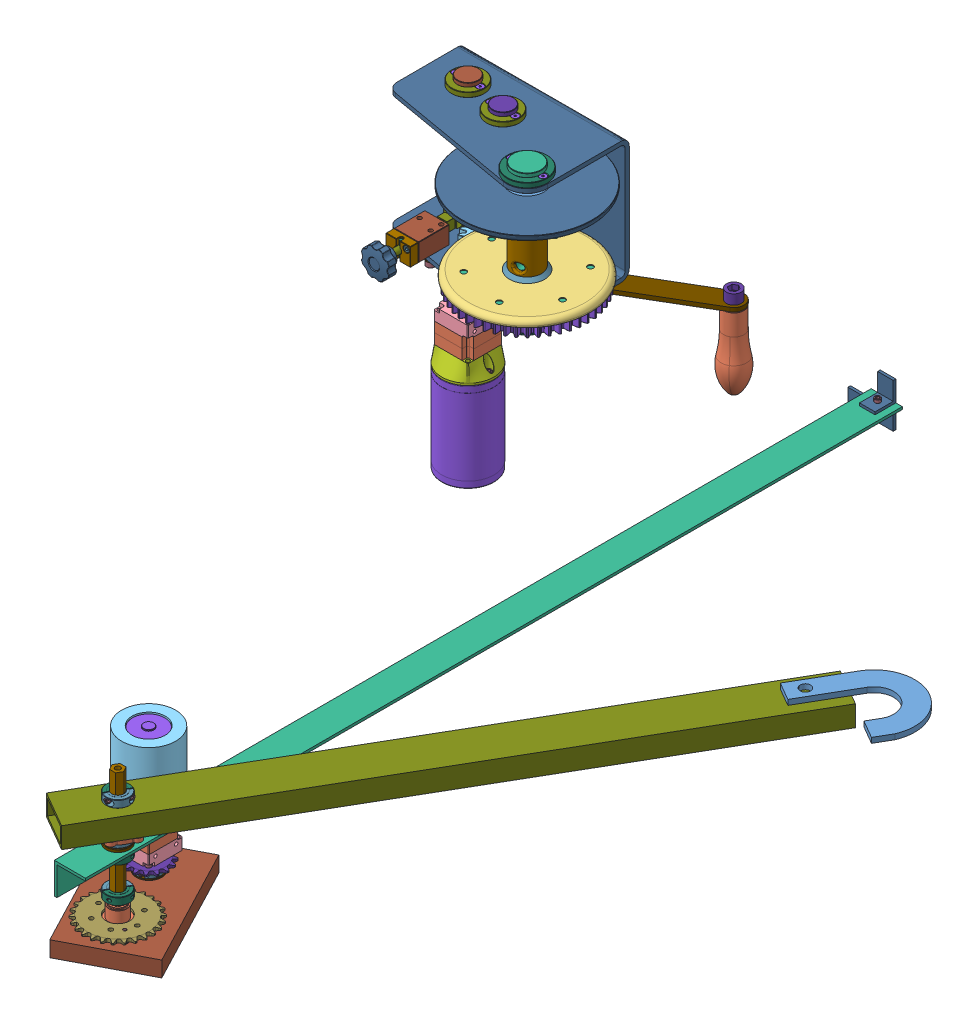
SolidWorks assembly Climber, configuration Default. Lengths in mm.
Overall size (953.37 422.19 1109.35).
186 component instances, 84 part files, 0 mates.
Components (placement in the parent):
- Climber.step-1: Climber.step [Default] at origin size (953.37 422.19 1109.35)
  - BAG 2 stage Release _1_.step-1: BAG 2 stage Release _1_.step [Default] at origin size (49.07 173.59 49.07)
    - 217-2625-100 _1_.step-1: 217-2625-100 _1_.step [Default] at origin size (48.74 12.7 48.74)
      - 217-2625-010 Rev1.step-1: 217-2625-010 Rev1.step [Default] at (-51.7575 -31.3954 849.6821) x (0.784104 0 0.62063) z (0 1 0) size (4 4 12)
      - 217-2625-005 Rev1_Planet_Revolving_Follower01.step-1: 217-2625-005 Rev1_Planet_Revolving_Follower01.step [Default] at (-38.1283 -28.6954 860.4699) x (0.955071 0 0.296378) z (0 1 0) size (16.91 16.91 8)
      - 217-2625-010 Rev1.step-2: 217-2625-010 Rev1.step [Default] at (-35.3114 -31.3954 842.9076) x (0.795957 0 0.605353) z (0 1 0) size (4 4 12)
      - 217-2625-005 Rev1_Planet_Revolving_Follower01.step-2: 217-2625-005 Rev1_Planet_Revolving_Follower01.step [Default] at (-35.3114 -28.6954 842.9076) x (0.979261 0 0.202601) z (0 1 0) size (16.91 16.91 8)
      - 217-2625-010 Rev1.step-3: 217-2625-010 Rev1.step [Default] at (-38.1283 -31.3954 860.4699) x (0.784104 0 0.62063) z (0 1 0) size (4 4 12)
      - 217-2625-005 Rev1_Planet_Revolving_Follower01.step-3: 217-2625-005 Rev1_Planet_Revolving_Follower01.step [Default] at (-51.7575 -28.6954 849.6821) x (-0.955094 0 -0.296304) z (0 1 0) size (16.91 16.91 8)
      - 217-2625-008 Rev1.step-1: 217-2625-008 Rev1.step [Default] at (-41.6375 -35.0454 850.9) x (0.784104 0 0.62063) z (0 1 0) size (34.7 34.7 4.7)
    - 217-2818 Rev1 _1_.step-1: 217-2818 Rev1 _1_.step [Default] at origin size (49.07 17.41 49.07)
      - 217-2725-002 Rev1_24t Planet.step-1: 217-2725-002 Rev1_24t Planet.step [Default] at (-29.5485 -41.3954 850.9) x (0.130526 0 0.991445) z (0 -1 0) size (13.17 13.17 8)
      - 217-2725-002 Rev1_24t Planet.step-2: 217-2725-002 Rev1_24t Planet.step [Default] at (-41.6375 -41.3954 838.811) x (0.991445 0 -0.130526) z (0 -1 0) size (13.17 13.17 8)
      - 217-2725-001 Rev1_24t Sun.step-1: 217-2725-001 Rev1_24t Sun.step [Default] at (-41.6375 -39.0454 850.9) x (1 0 0) z (0 1 0) size (13.12 13.14 12.7)
      - 217-2724-002 Rev1.step-1: 217-2724-002 Rev1.step [Default] at (-41.6375 -47.7454 850.9) x (0.707107 0 0.707107) z (0 -1 0) size (34.7 34.7 4.7)
      - 217-2625-010 Rev1.step-1: 217-2625-010 Rev1.step [Default] at (-53.7265 -44.0954 850.9) x (0.971612 0 0.236582) z (0 1 0) size (4 4 12)
      - 217-2725-001 Rev1_24t Sun-0.step-1: 217-2725-001 Rev1_24t Sun-0.step [Default] at (-41.6375 -39.0454 850.9) x (1 0 0) z (0 1 0) size (14.52 14.49 4.63)
      - 217-2625-010 Rev1.step-2: 217-2625-010 Rev1.step [Default] at (-41.6375 -44.0954 862.989) x (0.236582 0 -0.971612) z (0 1 0) size (4 4 12)
      - 217-2725-002 Rev1_24t Planet.step-3: 217-2725-002 Rev1_24t Planet.step [Default] at (-41.6375 -41.3954 862.989) x (-0.991445 0 0.130526) z (0 -1 0) size (13.17 13.17 8)
      - 217-2625-010 Rev1.step-3: 217-2625-010 Rev1.step [Default] at (-29.5485 -44.0954 850.9) x (-0.971612 0 -0.236582) z (0 1 0) size (4 4 12)
      - 217-2725-002 Rev1_24t Planet.step-4: 217-2725-002 Rev1_24t Planet.step [Default] at (-53.7265 -41.3954 850.9) x (-0.130526 0 -0.991445) z (0 -1 0) size (13.17 13.17 8)
      - 217-2625-010 Rev1.step-4: 217-2625-010 Rev1.step [Default] at (-41.6375 -44.0954 838.811) x (-0.236582 0 0.971612) z (0 1 0) size (4 4 12)
    - 217-3351.step-1: 217-3351.step [Default] at (-41.6375 -5.525 850.9) x (0 0 1) z (0 -1 0) size (40.4 40.4 81.5)
    - SSHCM004_SSHCM004070010C.step-1: SSHCM004_SSHCM004070010C.step [Default] at (-41.6375 -8.7 863.4) x (-0.451598 0 0.892221) z (0.892221 0 0.451598) size (7 14 7)
    - 217-2822-003 Rev4.step-1: 217-2822-003 Rev4.step [Default] at (-41.6375 -7.2 850.9) x (0 0 1) z (0 1 0) size (42 42 4.8)
    - TRUARC-MSH-15_98541A410.step-1: TRUARC-MSH-15_98541A410.step [Default] at (-41.6375 -51.6954 850.9) x (0 -1 0) z (0.980859 0 0.194721) size (1 19.6 17.4)
    - 217-2625-007 Rev1_Sun_Driver01.step-1: 217-2625-007 Rev1_Sun_Driver01.step [Default] at (-41.6375 -27.7575 850.9) x (0.564419 0 0.825488) z (0 1 0) size (15.29 15.29 4.9)
    - SSA_SSA0832-1750ZC.step-1: SSA_SSA0832-1750ZC.step [Default] at (-24.1375 -63.461 868.4) x (0.162252 0 -0.986749) z (-0.986749 0 -0.162252) size (6.73 48.51 6.73)
    - 217-2625-009 Rev1.step-1: 217-2625-009 Rev1.step [Default] at (-41.6375 -19.68 850.9) x (-0.609619 0 -0.792694) z (0 -1 0) size (18 18 13)
    - 217-2741.step-1: 217-2741.step [Default] at (-41.6375 -23.2 850.9) x (0 1 0) z (-0.951311 0 -0.308231) size (5 26 26)
    - 217-2625-003 Rev1.step-1: 217-2625-003 Rev1.step [Default] at (-41.6375 -59.8478 850.9) x (0.966651 0 0.256095) z (0 -1 0) size (17 17 64.13)
    - TRUARC-5103-68_97414A675_grv.step-1: TRUARC-5103-68_97414A675_grv.step [Default] at (-40.441 -17.5834 850.8651) x (0 -1 0) z (-0.029125 0 -0.999576) size (1.07 15.49 20.19)
    - SSA_SSA0832-0500ZC.step-1: SSA_SSA0832-0500ZC.step [Default] at (-24.1375 -5.525 868.4) x (-0.592766 0 0.805375) z (-0.805375 0 -0.592766) size (6.73 16.76 6.73)
    - SSS1032-0125ZB_94105A824.step-1: SSS1032-0125ZB_94105A824.step [Default] at (-36.1616 -14.205 846.6888) x (-0.605001 -0.122849 -0.78669) z (0.792694 0 -0.609619) size (4.88 4.88 3.18)
    - 217-2816-001 Rev1.step-1: 217-2816-001 Rev1.step [Default] at (-41.6375 -45.75 850.9) x (1 0 0) z (0 -1 0) size (42 42 14.52)
    - SSA_SSA0832-1750ZC.step-2: SSA_SSA0832-1750ZC.step [Default] at (-59.1375 -63.461 833.4) x (-0.769034 0 0.639207) z (0.639207 0 0.769034) size (6.73 48.51 6.73)
    - SPRGW0856-1102-012_9714K62.step-1: SPRGW0856-1102-012_9714K62.step [Default] at (-41.6375 -60.3002 850.9) x (-0.695225 0 -0.718792) z (-0.718792 0 0.695225) size (29.09 5.11 27.99)
    - 217-2625-002 Rev1.step-1: 217-2625-002 Rev1.step [Default] at (-41.6375 -45.6 850.9) x (1 0 0) z (0 1 0) size (42 42 17.12)
    - SSHCM004_SSHCM004070010C.step-2: SSHCM004_SSHCM004070010C.step [Default] at (-41.6375 -8.7 838.4) x (-0.447517 0 0.894275) z (0.894275 0 0.447517) size (7 14 7)
    - 217-2625-011 Rev1.step-1: 217-2625-011 Rev1.step [Default] at (-41.6375 -14.83 850.9) x (-0.792694 0 0.609619) z (-0.609619 0 -0.792694) size (8.01 7.5 7.94)
    - 217-2625-001 Rev1.step-1: 217-2625-001 Rev1.step [Default] at (-41.6375 -16.2 850.9) x (1 0 0) z (0 1 0) size (42 42 18)
    - 217-2742.step-1: 217-2742.step [Default] at (-41.6375 -59.3002 850.9) x (0 1 0) z (-1 0 0) size (7 28 28)
    - SSA_SSA0832-0500ZC.step-2: SSA_SSA0832-0500ZC.step [Default] at (-59.1375 -5.525 833.4) x (0.592766 0 -0.805375) z (0.805375 0 0.592766) size (6.73 16.76 6.73)
    - 217-2816-001 Rev1.step-2: 217-2816-001 Rev1.step [Default] at (-41.6375 -33.05 850.9) x (1 0 0) z (0 -1 0) size (42 42 14.52)
    - 217-2742.step-2: 217-2742.step [Default] at (-41.6375 -67.6002 850.9) x (0 1 0) z (-0.997393 0 -0.072165) size (7 28 28)
    - 217-2625-007 Rev1_Sun_Driver01-1.step-1: 217-2625-007 Rev1_Sun_Driver01-1.step [Default] at (-41.6375 -27.7575 850.9) x (0.564419 0 0.825488) z (0 1 0) size (5.61 5.61 12.73)
  - Winch _1_.step-1: Winch _1_.step [Default] at origin size (276.81 296.4 303.95)
    - Trava _1_.step-1: Trava _1_.step [Default] at origin size (34.12 40.11 100.61)
      - Tampa.step-1: Tampa.step [Default] at (-473.7719 -16.7958 103.4898) x (0 1 0) z (0.002101 0 0.999998) size (22 30 10)
      - Manípulo.step-1: Manípulo.step [Default] at (-473.7299 -16.7958 123.4898) x (-0.999998 0 0.002101) z (0 -1 0) size (34.07 22.72 40.11)
      - Corpo da Trava.step-1: Corpo da Trava.step [Default] at (-473.8517 -16.7958 65.4899) x (0 1 0) z (0.002101 0 0.999998) size (22 30 38)
      - Pino Elástico Ø4 x 18.step-1: Pino Elástico Ø4 x 18.step [Default] at (-473.7194 -7.7958 128.4898) x (0.999998 0 -0.002101) z (0.002101 0 0.999998) size (3.97 18 4)
      - Mola da Trava.step-1: Mola da Trava.step [Default] at (-473.8349 -16.7958 73.4774) x (0.36897 0.929441 -0.000775) z (0.002101 0 0.999998) size (9.78 9.32 31.6)
      - Paraf_Allen din_912-m4x16.step-1: Paraf_Allen din_912-m4x16.step [Default] at (-483.7851 -22.8208 109.1109) x (-0.135837 0.990731 0.000285) z (-0.990729 -0.135837 0.002081) size (7 20 7)
      - Pino Ø4.step-1: Pino Ø4.step [Default] at (-473.7591 -16.7958 109.5898) x (0 1 0) z (0.002101 0 0.999998) size (20 4 4)
      - Trava.step-1: Trava.step [Default] at (-473.8853 -16.7958 49.4899) x (0 1 0) z (0.002101 0 0.999998) size (12 12 93.84)
      - Paraf_Allen din_912-m4x16.step-2: Paraf_Allen din_912-m4x16.step [Default] at (-463.7351 -10.7707 109.0687) x (0.920984 0.389596 -0.001935) z (-0.389596 0.920986 0.000818) size (7 20 7)
    - Manivela _1_.step-1: Manivela _1_.step [Default] at origin size (246.75 124.4 162.81)
      - Paraf_Allen M12x40.step-1: Paraf_Allen M12x40.step [Default] at (-267.9374 -68.3958 -91.8376) x (0 -1 0) z (0.861383 0 -0.507957) size (52 18 18)
      - Manivela_Valor predeterminado_Como usinado_.step-1: Manivela_Valor predeterminado_Como usinado_.step [Default] at (-472.5158 -43.7958 28.8021) x (0 -1 0) z (0.861383 0 -0.507957) size (24.8 25 250)
      - Manivela_Valor predeterminado_Como usinado_-2.step-1: Manivela_Valor predeterminado_Como usinado_-2.step [Default] at (-472.5158 -43.7958 28.8021) x (0 -1 0) z (0.861383 0 -0.507957) size (3.01 25 15.5)
      - Manípulo-2.step-1: Manípulo-2.step [Default] at (-267.9374 -73.1958 -91.8376) x (0 -1 0) z (0.861383 0 -0.507957) size (95 36.6 36.6)
      - Manivela_Valor predeterminado_Como usinado_-3.step-1: Manivela_Valor predeterminado_Como usinado_-3.step [Default] at (-472.5158 -43.7958 28.8021) x (0 -1 0) z (0.861383 0 -0.507957) size (14 25 25)
      - Manivela_Valor predeterminado_Como usinado_-4.step-1: Manivela_Valor predeterminado_Como usinado_-4.step [Default] at (-472.5158 -43.7958 28.8021) x (0 -1 0) z (0.861383 0 -0.507957) size (3 25 15.5)
    - Anel de Trava Pesado Ø_16.step-1: Anel de Trava Pesado Ø_16.step [Default] at (-472.7311 -10.7458 28.9291) x (-0.999998 0 0.002101) z (0.002101 0 0.999998) size (18.28 1.5 22.98)
    - Paraf_Allen_din_7984_M8x14.step-1: Paraf_Allen_din_7984_M8x14.step [Default] at (-361.5212 -0.7958 33.4223) x (0 1 0) z (0.925025 0 0.379907) size (19 13 13)
    - Chaveta Eixo Ø25.step-1: Chaveta Eixo Ø25.step [Default] at (-346.4622 0.2042 77.4163) x (-0.946108 0 0.323851) z (-0.323851 0 -0.946108) size (8 11 7)
    - Paraf DIN 7991 M04x10.step-1: Paraf DIN 7991 M04x10.step [Default] at (-324.2095 -38.3958 85.4173) x (0 1 0) z (-0.925025 0 -0.379907) size (10 8 8)
    - Arruela de Pressão Ø6.step-1: Arruela de Pressão Ø6.step [Default] at (-483.8275 -36.3958 77.0109) x (-0.999998 0 0.002101) z (0.002101 0 0.999998) size (10.4 2 10.4)
    - Paraf DIN 7991 M04x10.step-2: Paraf DIN 7991 M04x10.step [Default] at (-435.0078 122.8042 38.7382) x (0 -1 0) z (0.002101 0 0.999998) size (10 8 8)
    - Carcaça do guincho.step-1: Carcaça do guincho.step [Default] at (-418.9198 42.2042 -14.5902) x (0 -1 0) z (0.002101 0 0.999998) size (150 200 125.21)
    - Paraf DIN 7991 M04x10.step-3: Paraf DIN 7991 M04x10.step [Default] at (-405.0079 122.8042 38.6751) x (0 -1 0) z (0.002101 0 0.999998) size (10 8 8)
    - Paraf DIN 7991 M04x10.step-4: Paraf DIN 7991 M04x10.step [Default] at (-435.0078 -38.3958 38.7382) x (0 1 0) z (-0.925025 0 -0.379907) size (10 8 8)
    - Arruela de Pressão Ø6.step-2: Arruela de Pressão Ø6.step [Default] at (-463.8139 -36.3958 83.4689) x (-0.999998 0 0.002101) z (0.002101 0 0.999998) size (10.4 2 10.4)
    - Paraf DIN 7991 M04x10.step-5: Paraf DIN 7991 M04x10.step [Default] at (-487.7311 -38.3958 28.9606) x (0 1 0) z (-0.925025 0 -0.379907) size (10 8 8)
    - Paraf DIN 7991 M04x10.step-6: Paraf DIN 7991 M04x10.step [Default] at (-487.7311 122.8042 28.9606) x (0 -1 0) z (0.002101 0 0.999998) size (10 8 8)
    - Eixo Ø16-01.step-1: Eixo Ø16-01.step [Default] at (-472.7311 128.2042 28.9291) x (0 -1 0) z (-0.861383 0 0.507957) size (187 26 26)
    - Chaveta Eixo Ø16.step-1: Chaveta Eixo Ø16.step [Default] at (-423.1058 0.2042 42.6313) x (0.784921 0 0.619596) z (-0.619596 0 0.784921) size (5 11 5)
    - Chaveta Eixo Ø16.step-2: Chaveta Eixo Ø16.step [Default] at (-477.038 -16.7958 31.4689) x (0.507957 0 0.861383) z (-0.861383 0 0.507957) size (5 11 5)
    - Paraf_Allen din_912-m6x25.step-1: Paraf_Allen din_912-m6x25.step [Default] at (-463.8412 -36.3958 70.4689) x (0.999998 0 -0.002101) z (0.002101 0 0.999998) size (10 31 10)
    - Paraf_Allen_din_7984_M8x14.step-2: Paraf_Allen_din_7984_M8x14.step [Default] at (-379.868 -0.7958 126.9017) x (0 1 0) z (0.925025 0 0.379907) size (19 13 13)
    - Anel de Trava Pesado Ø_16.step-2: Anel de Trava Pesado Ø_16.step [Default] at (-420.0078 6.2542 38.7067) x (-0.999998 0 0.002101) z (0.002101 0 0.999998) size (18.28 1.5 22.98)
    - Anel de Trava Pesado Ø_16.step-3: Anel de Trava Pesado Ø_16.step [Default] at (-472.7311 -24.3458 28.9291) x (-0.999998 0 0.002101) z (0.002101 0 0.999998) size (18.28 1.5 22.98)
    - Paraf_Allen din_912-m6x25.step-2: Paraf_Allen din_912-m6x25.step [Default] at (-483.8275 -36.3958 77.0109) x (0.999998 0 -0.002101) z (0.002101 0 0.999998) size (10 31 10)
    - Paraf_Allen_din_7984_M8x14.step-3: Paraf_Allen_din_7984_M8x14.step [Default] at (-325.8977 -0.7958 137.4942) x (0 1 0) z (0.925025 0 0.379907) size (19 13 13)
    - Carretel_Valor predeterminado_Como usinado_.step-1: Carretel_Valor predeterminado_Como usinado_.step [Default] at (-343.7095 56.2042 85.4582) x (0 -1 0) z (0.323851 0 0.946108) size (4 43 43)
    - Paraf_Allen_din_7984_M8x14.step-4: Paraf_Allen_din_7984_M8x14.step [Default] at (-307.5509 -0.7958 44.0148) x (0 1 0) z (0.925025 0 0.379907) size (19 13 13)
    - Bucha Ø25.step-1: Bucha Ø25.step [Default] at (-343.7095 -27.7958 85.4582) x (-0.999998 0 0.002101) z (0.002101 0 0.999998) size (49 11.01 49)
    - Bucha Ø16.step-1: Bucha Ø16.step [Default] at (-420.0078 -27.7958 38.7067) x (-0.999998 0 0.002101) z (0.002101 0 0.999998) size (40 11.01 40)
    - Eixo Ø16-02.step-1: Eixo Ø16-02.step [Default] at (-420.0078 128.2042 38.7067) x (0 -1 0) z (-0.619596 0 0.784921) size (187 26 26)
    - Anel de Trava Pesado Ø_16.step-4: Anel de Trava Pesado Ø_16.step [Default] at (-472.7311 -40.3958 28.9291) x (-0.991846 0 0.127441) z (0.127441 0 0.991846) size (18.28 1.5 22.98)
    - Anel de Trava Pesado Ø_16.step-5: Anel de Trava Pesado Ø_16.step [Default] at (-420.0078 -7.4458 38.7067) x (-0.999998 0 0.002101) z (0.002101 0 0.999998) size (18.28 1.5 22.98)
    - Paraf_Allen_din_7984_M8x14.step-5: Paraf_Allen_din_7984_M8x14.step [Default] at (-397.6798 -0.7958 74.8657) x (0 1 0) z (-0.031468 0 -0.999505) size (19 13 13)
    - Arruela Lisa Ø6.step-1: Arruela Lisa Ø6.step [Default] at (-463.8139 -32.7958 83.4689) x (-0.002101 0 -0.999998) z (0 -1 0) size (12 12 1.6)
    - Anel de Trava Pesado Ø_16.step-6: Anel de Trava Pesado Ø_16.step [Default] at (-420.0078 -40.3958 38.7067) x (-0.999998 0 0.002101) z (0.002101 0 0.999998) size (18.28 1.5 22.98)
    - Arruela de Pressão Ø6.step-3: Arruela de Pressão Ø6.step [Default] at (-463.8412 -36.3958 70.4689) x (-0.999998 0 0.002101) z (0.002101 0 0.999998) size (10.4 2 10.4)
    - Paraf DIN 7991 M04x10.step-7: Paraf DIN 7991 M04x10.step [Default] at (-324.2095 122.8042 85.4173) x (0 -1 0) z (0.002101 0 0.999998) size (10 8 8)
    - Bucha Ø16.step-2: Bucha Ø16.step [Default] at (-472.7311 -27.7958 28.9291) x (-0.999998 0 0.002101) z (0.002101 0 0.999998) size (40 11.01 40)
    - Carretel_Valor predeterminado_Como usinado_-5.step-1: Carretel_Valor predeterminado_Como usinado_-5.step [Default] at (-343.7095 56.2042 85.4582) x (0 -1 0) z (0.323851 0 0.946108) size (2.83 40.66 40.66)
    - Anel de Trava Pesado Ø_16.step-7: Anel de Trava Pesado Ø_16.step [Default] at (-420.0078 -10.6458 38.7067) x (-0.999998 0 0.002101) z (0.002101 0 0.999998) size (18.28 1.5 22.98)
    - Anel Espaçador 21,8.step-1: Anel Espaçador 21,8.step [Default] at (-343.7095 -16.7958 85.4582) x (0 -1 0) z (0.002101 0 0.999998) size (21.8 35 35)
    - Arruela Lisa Ø6.step-2: Arruela Lisa Ø6.step [Default] at (-483.8275 -32.7958 77.0109) x (-0.002101 0 -0.999998) z (0 -1 0) size (12 12 1.6)
    - Paraf DIN 7991 M04x10.step-8: Paraf DIN 7991 M04x10.step [Default] at (-457.7311 -38.3958 28.8976) x (0 1 0) z (-0.925025 0 -0.379907) size (10 8 8)
    - Carretel_Valor predeterminado_Como usinado_-6.step-1: Carretel_Valor predeterminado_Como usinado_-6.step [Default] at (-343.7095 56.2042 85.4582) x (0 -1 0) z (0.323851 0 0.946108) size (8 154 154)
    - Bucha Ø25.step-2: Bucha Ø25.step [Default] at (-343.7095 112.2042 85.4582) x (0.999998 0 -0.002101) z (0.002101 0 0.999998) size (49 11.01 49)
    - Chaveta Eixo Ø16.step-3: Chaveta Eixo Ø16.step [Default] at (-423.1058 -16.7958 42.6313) x (0.784921 0 0.619596) z (-0.619596 0 0.784921) size (5 11 5)
    - Anel Espaçador 5,8.step-1: Anel Espaçador 5,8.step [Default] at (-343.7095 109.2042 85.4582) x (0 -1 0) z (0.002101 0 0.999998) size (5.8 35 35)
    - Bucha Ø16.step-3: Bucha Ø16.step [Default] at (-472.7311 112.2042 28.9291) x (0.999998 0 -0.002101) z (0.002101 0 0.999998) size (40 11.01 40)
    - Engrenagem-02.step-1: Engrenagem-02.step [Default] at (-420.0078 -10.7958 38.7067) x (0 -1 0) z (-0.619596 0 0.784921) size (12.03 77.48 77.48)
    - Eixo Ø25.step-1: Eixo Ø25.step [Default] at (-343.7095 128.2042 85.4582) x (0 -1 0) z (-0.323851 0 -0.946108) size (172 35 35)
    - Engrenagem-01.step-1: Engrenagem-01.step [Default] at (-420.0078 6.2042 38.7067) x (0 -1 0) z (-0.619596 0 0.784921) size (12 40.76 40.76)
    - Arruela Lisa Ø6.step-3: Arruela Lisa Ø6.step [Default] at (-463.8412 -32.7958 70.4689) x (-0.002101 0 -0.999998) z (0 -1 0) size (12 12 1.6)
    - Engrenagem-03.step-1: Engrenagem-03.step [Default] at (-343.7095 6.2042 85.4582) x (0 -1 0) z (-0.323851 0 -0.946108) size (12 149.76 149.76)
    - Paraf DIN 7991 M04x10.step-9: Paraf DIN 7991 M04x10.step [Default] at (-363.2094 -38.3958 85.4992) x (0 1 0) z (-0.925025 0 -0.379907) size (10 8 8)
    - Carretel_Valor predeterminado_Como usinado_-7.step-1: Carretel_Valor predeterminado_Como usinado_-7.step [Default] at (-343.7095 56.2042 85.4582) x (0 -1 0) z (0.323851 0 0.946108) size (100 35 35.01)
    - Paraf DIN 7991 M04x10.step-10: Paraf DIN 7991 M04x10.step [Default] at (-363.2094 122.8042 85.4992) x (0 -1 0) z (0.002101 0 0.999998) size (10 8 8)
    - Paraf_Allen_din_7984_M8x14.step-6: Paraf_Allen_din_7984_M8x14.step [Default] at (-289.7391 -0.7958 96.0507) x (0 1 0) z (0.925025 0 0.379907) size (19 13 13)
    - Bucha Ø16.step-4: Bucha Ø16.step [Default] at (-420.0078 112.2042 38.7067) x (0.999998 0 -0.002101) z (0.002101 0 0.999998) size (40 11.01 40)
    - Anel de Trava Pesado Ø_16.step-8: Anel de Trava Pesado Ø_16.step [Default] at (-420.0078 -24.4458 38.7067) x (-0.999998 0 0.002101) z (0.002101 0 0.999998) size (18.28 1.5 22.98)
    - Paraf DIN 7991 M04x10.step-11: Paraf DIN 7991 M04x10.step [Default] at (-457.7311 122.8042 28.8976) x (0 -1 0) z (0.002101 0 0.999998) size (10 8 8)
    - Engrenagem-01.step-2: Engrenagem-01.step [Default] at (-472.7311 -10.7958 28.9291) x (0 -1 0) z (-0.861383 0 0.507957) size (12 40.76 40.76)
    - Paraf_Allen din_912-m6x25.step-3: Paraf_Allen din_912-m6x25.step [Default] at (-463.8139 -36.3958 83.4689) x (0.999998 0 -0.002101) z (0.002101 0 0.999998) size (10 31 10)
    - Carretel_Valor predeterminado_Como usinado_-8.step-1: Carretel_Valor predeterminado_Como usinado_-8.step [Default] at (-343.7095 56.2042 85.4582) x (0 -1 0) z (0.323851 0 0.946108) size (8 160 160)
    - Carretel_Valor predeterminado_Como usinado_-9.step-1: Carretel_Valor predeterminado_Como usinado_-9.step [Default] at (-343.7095 56.2042 85.4582) x (0 -1 0) z (0.323851 0 0.946108) size (4 43 43)
    - Paraf DIN 7991 M04x10.step-12: Paraf DIN 7991 M04x10.step [Default] at (-405.0079 -38.3958 38.6751) x (0 1 0) z (-0.925025 0 -0.379907) size (10 8 8)
    - Carretel_Valor predeterminado_Como usinado_-10.step-1: Carretel_Valor predeterminado_Como usinado_-10.step [Default] at (-343.7095 56.2042 85.4582) x (0 -1 0) z (0.323851 0 0.946108) size (2.83 40.66 40.66)
  - 217-4106S-STEP-20140806 _1_.step-1: 217-4106S-STEP-20140806 _1_.step [Default] at origin size (39.04 9.53 39.04)
    - 217-4106-003 Rev2_90128A192.step-1: 217-4106-003 Rev2_90128A192.step [Default] at (-11.2772 8.6258 935.7225) x (-0.501473 0 0.865173) z (-0.865173 0 -0.501473) size (6.86 6.86 13.69)
    - 217-4106-002 Rev2.step-1: 217-4106-002 Rev2.step [Default] at (0 8.6258 930.275) x (-0.501473 0 0.865173) z (0 1 0) size (28.56 13.79 9.53)
    - 217-4106-003 Rev2_90128A192.step-2: 217-4106-003 Rev2_90128A192.step [Default] at (-0.8785 8.6258 917.7819) x (-0.501473 0 0.865173) z (-0.865173 0 -0.501473) size (6.86 6.86 13.69)
    - 217-4106-001 Rev2.step-1: 217-4106-001 Rev2.step [Default] at (0 8.6258 930.275) x (0.501473 0 -0.865173) z (0 1 0) size (28.56 13.79 9.53)
  - BAG 2 stage Release _2_.step-1: BAG 2 stage Release _2_.step [Default] at origin size (42 64.13 42)
    - 217-2742.step-1: 217-2742.step [Default] at (-472.7311 -125.8458 28.9291) x (0 -1 0) z (1 0 0) size (7 28 28)
    - 217-2742.step-2: 217-2742.step [Default] at (-472.7311 -117.5458 28.9291) x (0 -1 0) z (0.997393 0 -0.072165) size (7 28 28)
    - TRUARC-MSH-15_98541A410.step-1: TRUARC-MSH-15_98541A410.step [Default] at (-472.7311 -133.4506 28.9291) x (0 1 0) z (-0.980859 0 0.194721) size (1 19.6 17.4)
    - 217-2625-003 Rev1.step-1: 217-2625-003 Rev1.step [Default] at (-472.7311 -125.2982 28.9291) x (-0.966651 0 0.256095) z (0 1 0) size (17 17 64.13)
    - SPRGW0856-1102-012_9714K62.step-1: SPRGW0856-1102-012_9714K62.step [Default] at (-472.7311 -124.8458 28.9291) x (0.695225 0 -0.718792) z (0.718792 0 0.695225) size (29.09 5.11 27.99)
    - 217-2625-002 Rev1.step-1: 217-2625-002 Rev1.step [Default] at (-472.7311 -139.546 28.9291) x (-1 0 0) z (0 -1 0) size (42 42 17.12)
  - 217-4106-001 Rev2.step-1: 217-4106-001 Rev2.step [Default] at (-41.6375 -84.9527 850.9) x (0.256095 0 -0.966651) z (0 1 0) size (28.56 13.79 9.53)
  - 217-4106-002 Rev2.step-1: 217-4106-002 Rev2.step [Default] at (0 -9.1542 930.275) x (0.501473 0 -0.865173) z (0 1 0) size (28.56 13.79 9.53)
  - Part 1.step-1: Part 1.step [Default] at (327.9884 33.3908 364.4084) x (-0.865173 0 -0.501473) z (-0.501473 0 0.865173) size (50.8 25.4 711.2)
  - 217-4106-003 Rev2_90128A192.step-1: 217-4106-003 Rev2_90128A192.step [Default] at (-11.2772 51.1708 935.7225) x (-0.501473 0 0.865173) z (-0.865173 0 -0.501473) size (6.86 6.86 13.69)
  - 217-2660.20121204.step-1: 217-2660.20121204.step [Default] at (-41.6375 -77.7422 850.9) x (0.966651 0 0.256095) z (0 1 0) size (50.15 50.42 10.7)
  - am-2986 FR8ZZ Hex Bearing.step-1: am-2986 FR8ZZ Hex Bearing.step [Default] at (0 -96.139 930.275) x (-0.463218 0 -0.886245) z (0 1 0) size (31.12 31.12 7.93)
  - 217-4106-003 Rev2_90128A192.step-2: 217-4106-003 Rev2_90128A192.step [Default] at (0.8785 -52.1342 942.7681) x (0.501473 0 -0.865173) z (0.865173 0 0.501473) size (6.86 6.86 13.69)
  - 217-4106-003 Rev2_90128A192.step-3: 217-4106-003 Rev2_90128A192.step [Default] at (0 -6.35 0) x (1 0 0) z (0 -1 0) size (6.86 6.86 13.69)
  - 217-4106-003 Rev2_90128A192.step-4: 217-4106-003 Rev2_90128A192.step [Default] at (-20.6019 -72.4637 918.3337) x (0.865173 0 0.501473) z (0 1 0) size (6.86 6.86 13.69)
  - Part 1-11.step-1: Part 1-11.step [Default] at (317.161 46.0908 402.17) x (0.865173 0 0.501473) z (0.501473 0 -0.865173) size (99.06 6.35 120.49)
  - 217-4106-003 Rev2_90128A192.step-5: 217-4106-003 Rev2_90128A192.step [Default] at (-498.1311 -186.9072 28.9291) x (-1 0 0) z (0 -1 0) size (6.86 6.86 13.69)
  - 217-4106-003 Rev2_90128A192.step-6: 217-4106-003 Rev2_90128A192.step [Default] at (-447.3311 -186.9072 28.9291) x (-1 0 0) z (0 -1 0) size (6.86 6.86 13.69)
  - 217-4106-001 Rev2.step-2: 217-4106-001 Rev2.step [Default] at (0 51.1708 930.275) x (0.501473 0 -0.865173) z (0 1 0) size (28.56 13.79 9.53)
  - 217-4106-002 Rev2.step-2: 217-4106-002 Rev2.step [Default] at (0 -52.1342 930.275) x (0.501473 0 -0.865173) z (0 1 0) size (28.56 13.79 9.53)
  - 217-4106-003 Rev2_90128A192.step-7: 217-4106-003 Rev2_90128A192.step [Default] at (-51.0835 -84.9527 859.1234) x (-0.256095 0 0.966651) z (-0.966651 0 -0.256095) size (6.86 6.86 13.69)
  - 217-4106-003 Rev2_90128A192.step-8: 217-4106-003 Rev2_90128A192.step [Default] at (0.8785 -9.1542 942.7681) x (0.501473 0 -0.865173) z (0.865173 0 0.501473) size (6.86 6.86 13.69)
  - 217-4106-003 Rev2_90128A192.step-9: 217-4106-003 Rev2_90128A192.step [Default] at (-11.9413 25.4533 950.8769) x (-0.865173 0 -0.501473) z (0 1 0) size (6.86 6.86 13.69)
  - am-4124 500 Hex Hub.step-1: am-4124 500 Hex Hub.step [Default] at (38.4067 -79.7662 922.3884) x (-0.865173 0 -0.501473) z (0 1 0) size (58.55 52.17 25.4)
  - 217-4106-001 Rev2.step-3: 217-4106-001 Rev2.step [Default] at (0 -52.1342 930.275) x (-0.501473 0 0.865173) z (0 1 0) size (28.56 13.79 9.53)
  - am-2986 FR8ZZ Hex Bearing.step-2: am-2986 FR8ZZ Hex Bearing.step [Default] at (-41.8389 -96.139 850.2273) x (-0.886245 0 0.463218) z (0 1 0) size (31.12 31.12 7.93)
  - 217-4106-001 Rev2.step-4: 217-4106-001 Rev2.step [Default] at (0 -9.1542 930.275) x (-0.501473 0 0.865173) z (0 1 0) size (28.56 13.79 9.53)
  - Part 1-12.step-1: Part 1-12.step [Default] at (-472.7311 -62.8458 28.9291) x (0.256095 0 0.966651) z (0.966651 0 -0.256095) size (18.33 19.05 15.88)
  - am-2986 FR8ZZ Hex Bearing.step-3: am-2986 FR8ZZ Hex Bearing.step [Default] at (0 3.2283 930.275) x (0 0 1) z (0 -1 0) size (31.12 31.12 7.93)
  - 217-2816-001 Rev1.step-1: 217-2816-001 Rev1.step [Default] at (-472.7311 -151.685 28.9291) x (-1 0 0) z (0 1 0) size (42 42 14.52)
  - 217-4106-003 Rev2_90128A192.step-10: 217-4106-003 Rev2_90128A192.step [Default] at (20.6019 -75.0037 942.2163) x (0.865173 0 0.501473) z (0 1 0) size (6.86 6.86 13.69)
  - 217-4106-003 Rev2_90128A192.step-11: 217-4106-003 Rev2_90128A192.step [Default] at (11.2772 -52.1342 924.8275) x (0.501473 0 -0.865173) z (0.865173 0 0.501473) size (6.86 6.86 13.69)
  - 217-4106-003 Rev2_90128A192.step-12: 217-4106-003 Rev2_90128A192.step [Default] at (-14.2875 -19.05 0) x (0 0 -1) z (1 0 0) size (6.86 6.86 13.69)
  - Part 1-13.step-1: Part 1-13.step [Default] at (-472.7311 -94.5958 28.9291) x (0.256095 0 0.966651) z (-0.966651 0 0.256095) size (22.42 50.81 22.42)
  - 217-4106-003 Rev2_90128A192.step-13: 217-4106-003 Rev2_90128A192.step [Default] at (-26.9875 -12.7 838.2) x (0 -1 0) z (-1 0 0) size (6.86 6.86 13.69)
  - Part 1-14.step-1: Part 1-14.step [Default] at (-41.6375 0.475 850.9) x (-1 0 0) z (0 0 1) size (66.04 63.5 66.04)
  - 217-2816-001 Rev1.step-2: 217-2816-001 Rev1.step [Default] at (-472.7311 -139.385 28.9291) x (-1 0 0) z (0 1 0) size (42 42 14.52)
  - Part 1-15.step-1: Part 1-15.step [Default] at (-20.6375 0 987.425) x (0 0 -1) z (0 -1 0) size (1000.12 38.1 38.1)
  - 217-4106-002 Rev2.step-3: 217-4106-002 Rev2.step [Default] at (-41.6375 -84.9527 850.9) x (-0.256095 0 0.966651) z (0 1 0) size (28.56 13.79 9.53)
  - 217-4106-003 Rev2_90128A192.step-14: 217-4106-003 Rev2_90128A192.step [Default] at (-0.8785 51.1708 917.7819) x (-0.501473 0 0.865173) z (-0.865173 0 -0.501473) size (6.86 6.86 13.69)
  - 217-4018-STEP-20140806.step-1: 217-4018-STEP-20140806.step [Default] at (-472.7311 -167.8572 28.9291) size (64.01 21.62 64.01)
  - 217-4106-003 Rev2_90128A192.step-15: 217-4106-003 Rev2_90128A192.step [Default] at (-26.9875 -12.7 863.6) x (0 -1 0) z (-1 0 0) size (6.86 6.86 13.69)
  - 217-4106-002 Rev2.step-4: 217-4106-002 Rev2.step [Default] at (0 51.1708 930.275) x (-0.501473 0 0.865173) z (0 1 0) size (28.56 13.79 9.53)
  - 217-4106-003 Rev2_90128A192.step-16: 217-4106-003 Rev2_90128A192.step [Default] at (-45.773 -84.9527 839.0785) x (-0.256095 0 0.966651) z (-0.966651 0 -0.256095) size (6.86 6.86 13.69)
  - CIM Motor.step-1: CIM Motor.step [Default] at (-472.7311 -179.3822 28.9291) x (0 -1 0) z (1 0 0) size (150.2 64.01 64.01)
  - 217-4106-003 Rev2_90128A192.step-17: 217-4106-003 Rev2_90128A192.step [Default] at (11.9413 25.4533 909.6731) x (-0.865173 0 -0.501473) z (0 1 0) size (6.86 6.86 13.69)
  - 217-4106-003 Rev2_90128A192.step-18: 217-4106-003 Rev2_90128A192.step [Default] at (11.2772 -9.1542 924.8275) x (0.501473 0 -0.865173) z (0.865173 0 0.501473) size (6.86 6.86 13.69)
  - Part 1-16.step-1: Part 1-16.step [Default] at (0 79.4283 930.275) x (-0.501473 0 0.865173) z (-0.865173 0 -0.501473) size (14.66 177.8 12.7)
  - am-4124 500 Hex Hub.step-2: am-4124 500 Hex Hub.step [Default] at (7.8866 20.6908 968.6817) x (0.501473 0 -0.865173) z (0 1 0) size (58.55 52.17 25.4)
  - Part 1-17.step-1: Part 1-17.step [Default] at (9.525 -1.842 -12.7) x (0 -1 0) z (0 0 1) size (25.4 19.05 25.4)
  - Part 1-18.step-1: Part 1-18.step [Default] at (-22.0607 -89.7357 888.0676) x (0.886245 0 -0.463218) z (0.463218 0 0.886245) size (101.6 19.05 165.1)
  - am-0218_Plate Sprocket.step-1: am-0218_Plate Sprocket.step [Default] at (0 -77.6326 930.275) x (-0.865173 0 -0.501473) z (0 1 0) size (83.87 84.35 4.29)
  - Part 1-17.step-2: Part 1-17.step [Default] at (-19.3045 -28.575 -12.7) x (-1 0 0) z (0 0 1) size (25.4 19.05 25.4)
  - Part 1-17.step-3: Part 1-17.step [Default] at (-9.525 -1.333 -12.7) x (0 1 0) z (0 0 1) size (25.4 19.05 25.4)
